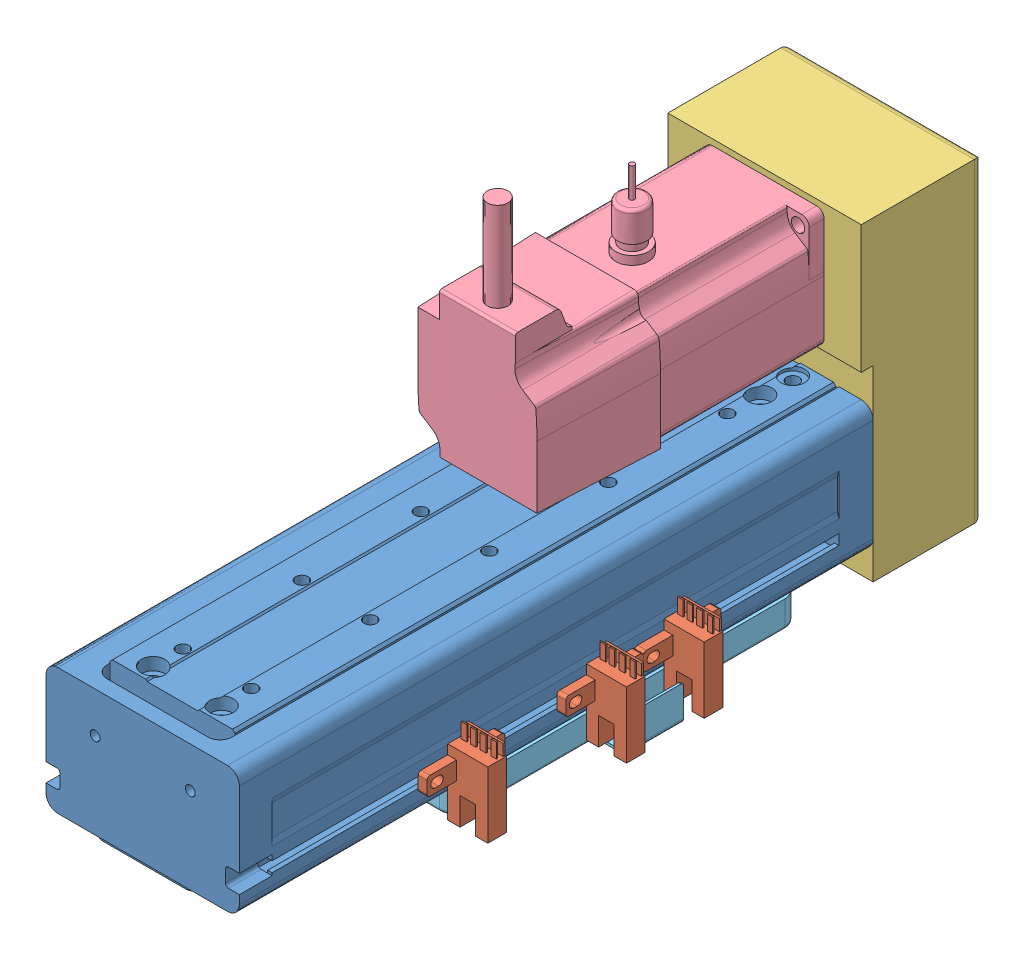
SolidWorks assembly S6M-BM-100W, configuration 默认. Lengths in mm.
Overall size (78.5 146.2 253.24).
7 component instances, 5 part files, 26 mates.
Components (placement in the parent):
- S6S-BL滑块滑轨(CPC)BR-BL-BM共用^S6M-BM-100W-1: S6S-BL滑块滑轨(CPC)BR-BL-BM共用^S6M-BM-100W [默认] x (-1 0 0) z (0 0 1) size (65 44.9 219.73) (virtual)
- 传感器^S6M-BM-100W-1: 传感器^S6M-BM-100W [默认] at (39.25 -39.2 135.7) size (13.5 27.2 26.1) (virtual)
- 传感器^S6M-BM-100W-2: 传感器^S6M-BM-100W [默认] at (39.25 -39.2 63) size (13.5 27.2 26.1) (virtual)
- 传感器^S6M-BM-100W-3: 传感器^S6M-BM-100W [默认] at (39.25 -39.2 89.1) size (13.5 27.2 26.1) (virtual)
- S5-BM-M10电机安装板^S6M-BM-100W-1: S5-BM-M10电机安装板^S6M-BM-100W [默认] at (0 -42.0332 -1) x (0 -1 0) z (1 0 0) size (106 41 65) (virtual)
- 复件 M10^S6M-BM-100W-1: 复件 M10^S6M-BM-100W [默认] at (0 31.5 59) x (-1 0 0) z (0 0 1) size (42.1 79.78 121.76) (virtual)
- S6-BC滑块组件^S6M-BM-100W-1: S6-BC滑块组件^S6M-BM-100W [Default] at (0 -1.5 161.7) x (1 0 0) z (0 1 0) size (69.5 116 25.18) (virtual)
Mates (geometry in assembly coordinates):
- 重合88: coincident: plane of 传感器^S6M-BM-100W-1 through (35.5 -37.4 125.8) normal (0 -1 0); plane of 传感器^S6M-BM-100W-2 through (35.5 -37.4 53.1) normal (0 -1 0)
- 重合92: coincident: plane of 传感器^S6M-BM-100W-2 through (35.5 -37.4 53.1) normal (0 -1 0); plane of 传感器^S6M-BM-100W-3 through (35.5 -37.4 79.2) normal (0 -1 0)
- 重合93: coincident: plane of 传感器^S6M-BM-100W-2 through (35.5 -31.3 79.2) normal (0 0 1); plane of 传感器^S6M-BM-100W-3 through (35.5 -31.3 79.2) normal (0 0 -1)
- 重合176: coincident: plane of 传感器^S6M-BM-100W-2 through (35.5 -31.3 79.2) normal (0 0 1); plane of 传感器^S6M-BM-100W-3 through (35.5 -31.3 79.2) normal (0 0 -1)
- 重合233: coincident: plane of S6-BC滑块组件^S6M-BM-100W-1; plane of assembly through (0 0 0) normal (1 0 0)
- 同心194: concentric: cylinder of S5-BM-M10电机安装板^S6M-BM-100W-1 through (0 31.5 3) axis (0 0 -1) radius 7.5; cylinder of 复件 M10^S6M-BM-100W-1 through (0 31.5 -22) axis (0 0 1) radius 4
- 重合241: coincident: plane of S5-BM-M10电机安装板^S6M-BM-100W-1 through (32.5 10.5 3) normal (0 0 1); plane of 复件 M10^S6M-BM-100W-1 through (-77.9984 32.9978 3) normal (0 0 -1)
- 角度1: planar angle = 3.141593 rad: plane of 复件 M10^S6M-BM-100W-1 through (-20 51.5 3) normal (-1 0 0); plane of S5-BM-M10电机安装板^S6M-BM-100W-1 through (32.5 -42.0332 -1) normal (1 0 0)
- 重合246: coincident: plane of 传感器^S6M-BM-100W-2 through (35.5 -37.4 53.1) normal (1 0 0); plane of 传感器^S6M-BM-100W-3 through (35.5 -37.4 79.2) normal (1 0 0)
- 距离1: distance = 56 mm: plane of S6-BC滑块组件^S6M-BM-100W-1 through (21 -56 99.2) normal (0 -1 0); plane of S6S-BL滑块滑轨(CPC)BR-BL-BM共用^S6M-BM-100W-1 through (0 0 202) normal (0 1 0)
- 重合248: coincident: plane of 传感器^S6M-BM-100W-2 through (46 -50.3 69.3) normal (1 0 0); plane of 传感器^S6M-BM-100W-3 through (46 -50.3 95.4) normal (1 0 0)
- 重合249: coincident: plane of 传感器^S6M-BM-100W-1 through (46 -50.3 142) normal (1 0 0); plane of 传感器^S6M-BM-100W-3 through (46 -50.3 95.4) normal (1 0 0)
- 重合250: coincident: plane of 传感器^S6M-BM-100W-2 through (32.5 -28.1 69.3) normal (0 1 0); plane of 传感器^S6M-BM-100W-3 through (32.5 -28.1 95.4) normal (0 1 0)
- 重合251: coincident: plane of 传感器^S6M-BM-100W-1 through (32.5 -28.1 142) normal (0 1 0); plane of 传感器^S6M-BM-100W-3 through (32.5 -28.1 95.4) normal (0 1 0)
- 距离3: distance = 8.6 mm: plane of S5-BM-M10电机安装板^S6M-BM-100W-1 through (-32.5 -52.5 3) normal (0 -1 0); plane of S6S-BL滑块滑轨(CPC)BR-BL-BM共用^S6M-BM-100W-1 through (0 -43.9 -67.1611) normal (0 -1 0)
- 距离5: distance = 70 mm: plane of 传感器^S6M-BM-100W-1 through (46 -28.1 142) normal (0 0 1); plane of S6S-BL滑块滑轨(CPC)BR-BL-BM共用^S6M-BM-100W-1 through (0 0 212) normal (0 0 1)
- 重合257: coincident: plane of S6S-BL滑块滑轨(CPC)BR-BL-BM共用^S6M-BM-100W-1 through (0 0 -1) normal (0 0 -1); plane of S5-BM-M10电机安装板^S6M-BM-100W-1 through (32.5 -55.5 -1) normal (0 0 1)
- 重合258: coincident: plane of S6S-BL滑块滑轨(CPC)BR-BL-BM共用^S6M-BM-100W-1 through (32.5 -39.9 -67.1611) normal (1 0 0); plane of 传感器^S6M-BM-100W-1 through (32.5 -50.3 142) normal (-1 0 0)
- 距离7: distance = 28.1 mm: plane of 传感器^S6M-BM-100W-1 through (32.5 -28.1 142) normal (0 1 0); plane of S6S-BL滑块滑轨(CPC)BR-BL-BM共用^S6M-BM-100W-1 through (0 0 202) normal (0 1 0)
- 重合260: coincident: plane of S6S-BL滑块滑轨(CPC)BR-BL-BM共用^S6M-BM-100W-1; plane of S6-BC滑块组件^S6M-BM-100W-1
- 重合261: coincident: plane of S6S-BL滑块滑轨(CPC)BR-BL-BM共用^S6M-BM-100W-1; plane of assembly through (0 0 0) normal (1 0 0)
- 重合262: coincident: plane of S6S-BL滑块滑轨(CPC)BR-BL-BM共用^S6M-BM-100W-1; plane of assembly through (0 0 0) normal (0 1 0)
- 重合263: coincident: plane of S6S-BL滑块滑轨(CPC)BR-BL-BM共用^S6M-BM-100W-1 through (0 0 0) normal (0 0 1); plane of assembly through (0 0 0) normal (0 0 1)
- 宽度1: width: plane of S6S-BL滑块滑轨(CPC)BR-BL-BM共用^S6M-BM-100W-1 through (32.5 -39.9 -67.1611) normal (1 0 0); plane of S6S-BL滑块滑轨(CPC)BR-BL-BM共用^S6M-BM-100W-1 through (-32.5 -14.4 -67.1611) normal (-1 0 0); plane of S5-BM-M10电机安装板^S6M-BM-100W-1 through (-32.5 -42.0332 -1) normal (-1 0 0); plane of S5-BM-M10电机安装板^S6M-BM-100W-1 through (32.5 -42.0332 -1) normal (1 0 0)
- 距离8: distance = 101 mm: plane of 传感器^S6M-BM-100W-2 through (46 -28.1 63) normal (0 0 -1); plane of S5-BM-M10电机安装板^S6M-BM-100W-1 through (0 -42.0332 -38) normal (0 0 -1)
- 宽度2: width: plane of 传感器^S6M-BM-100W-2 through (46 -28.1 69.3) normal (0 0 1); plane of 传感器^S6M-BM-100W-3 through (46 -28.1 89.1) normal (0 0 -1); plane of S6-BC滑块组件^S6M-BM-100W-1 through (28.75 -49.4 69.7) normal (0 0 -1); plane of S6-BC滑块组件^S6M-BM-100W-1 through (28.75 -49.4 88.7) normal (0 0 1)
